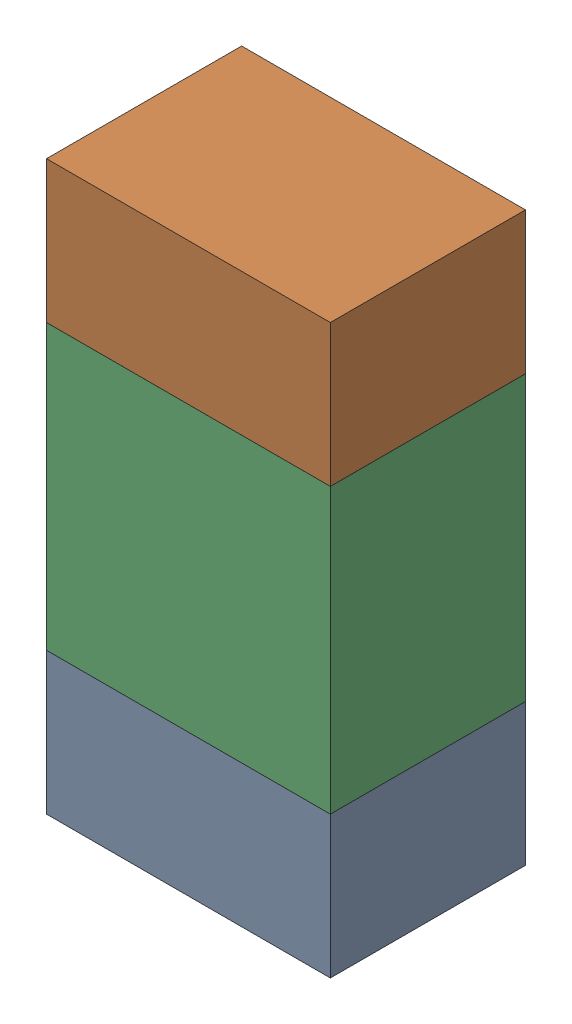
SolidWorks assembly R7, configuration ﾃﾞﾌｫﾙﾄ. Lengths in mm.
Overall size (0.8 1.6 0.55).
6 component instances, 2 part files, 0 mates.
Components (placement in the parent):
- 689261784-1: 689261784 [ﾃﾞﾌｫﾙﾄ] at (11.7499 24.1501 0) size (0.8 0.4 0.55)
  - Extruded_34-1: Extruded_34 [ﾃﾞﾌｫﾙﾄ] at origin size (0.8 0.4 0.55)
- 689261784-2: 689261784 [ﾃﾞﾌｫﾙﾄ] at (11.7499 25.3501 0) size (0.8 0.4 0.55)
  - Extruded_34-1: Extruded_34 [ﾃﾞﾌｫﾙﾄ] at origin size (0.8 0.4 0.55)
- 689261648-1: 689261648 [ﾃﾞﾌｫﾙﾄ] at (11.7499 24.75 0) size (0.8 0.8 0.55)
  - Extruded_33-1: Extruded_33 [ﾃﾞﾌｫﾙﾄ] at origin size (0.8 0.8 0.55)
